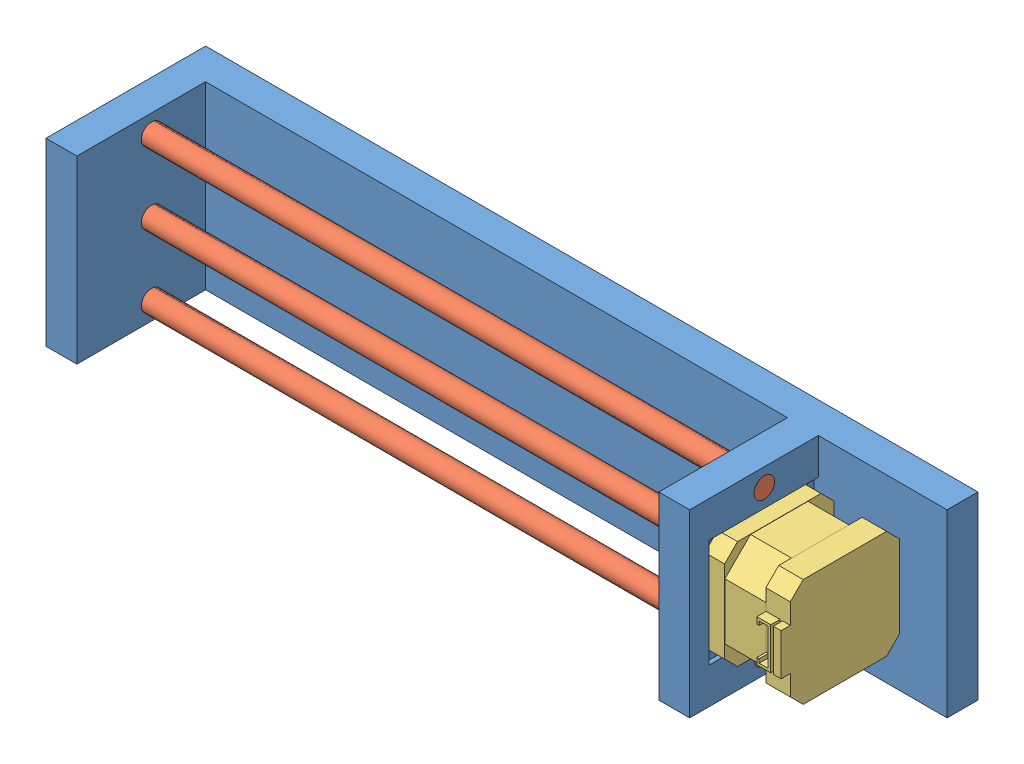
SolidWorks assembly Ensamblaje_Link1.2, configuration Predeterminado. Lengths in mm.
Overall size (300 70 62).
5 component instances, 3 part files, 12 mates.
Components (placement in the parent):
- Pieza1-1: Pieza1 [Predeterminado] x (0 1 0) z (1 0 0) size (70 62 300)
- Pieza2-1: Pieza2 [Predeterminado] at (-125 -28 33) size (250 8 8)
- Pieza2-2: Pieza2 [Predeterminado] at (-125 0 33) size (250 8 8)
- Pieza2-3: Pieza2 [Predeterminado] at (-125 28 33) size (250 8 8)
- Motor Paso a Paso-1: Motor Paso a Paso [Predeterminado] at (156.5 0 33.2) x (0 1 0) z (0 0 1) size (42 55.2 46)
Mates (geometry in assembly coordinates):
- Coincidente5: coincident aligned: plane of Pieza1-1 through (0 0 0) normal (0 0 1)
- Coincidente6: coincident aligned: plane of Pieza1-1 through (0 0 0) normal (0 1 0)
- Coincidente7: coincident aligned: plane of Pieza1-1 through (0 0 0) normal (1 0 0)
- Concéntrica1: concentric anti-aligned: cylinder of Pieza1-1 through (-136.3137 28 33) axis (1 0 0) radius 4; cylinder of Pieza2-3 through (125 28 33) axis (-1 0 0) radius 4
- Concéntrica2: concentric aligned: cylinder of Pieza1-1 through (-113 0 33) axis (-1 0 0) radius 4; cylinder of Pieza2-2 through (125 0 33) axis (-1 0 0) radius 4
- Concéntrica3: concentric anti-aligned: cylinder of Pieza1-1 through (-136.3137 -28 33) axis (1 0 0) radius 4; cylinder of Pieza2-1 through (125 -28 33) axis (-1 0 0) radius 4
- Coincidente8: coincident aligned: plane of Pieza1-1 through (125 -35 12) normal (1 0 0); plane of Pieza2-1 through (125 -28 33) normal (1 0 0)
- Coincidente9: coincident aligned: plane of Pieza1-1 through (125 -35 12) normal (1 0 0); plane of Pieza2-3 through (125 28 33) normal (1 0 0)
- Coincidente10: coincident aligned: plane of Pieza1-1 through (-125 -35 12) normal (-1 0 0); plane of Pieza2-2 through (-125 0 33) normal (-1 0 0)
- Coincidente11: coincident: plane of Pieza1-1 through (123.3 -21 54.4) normal (0 0 -1); plane of Motor Paso a Paso-1 through (123.3 -16 54.4) normal (0 0 1)
- Concéntrica4: concentric: cylinder of Pieza1-1 through (121.3 0 33.2) axis (1 0 0) radius 11; cylinder of Motor Paso a Paso-1 through (121.3 0 33.2) axis (1 0 0) radius 11
- Coincidente12: coincident anti-aligned: plane of Pieza1-1 through (123.3 0 0) normal (1 0 0); plane of Motor Paso a Paso-1 through (123.3 0 33.2) normal (-1 0 0)
